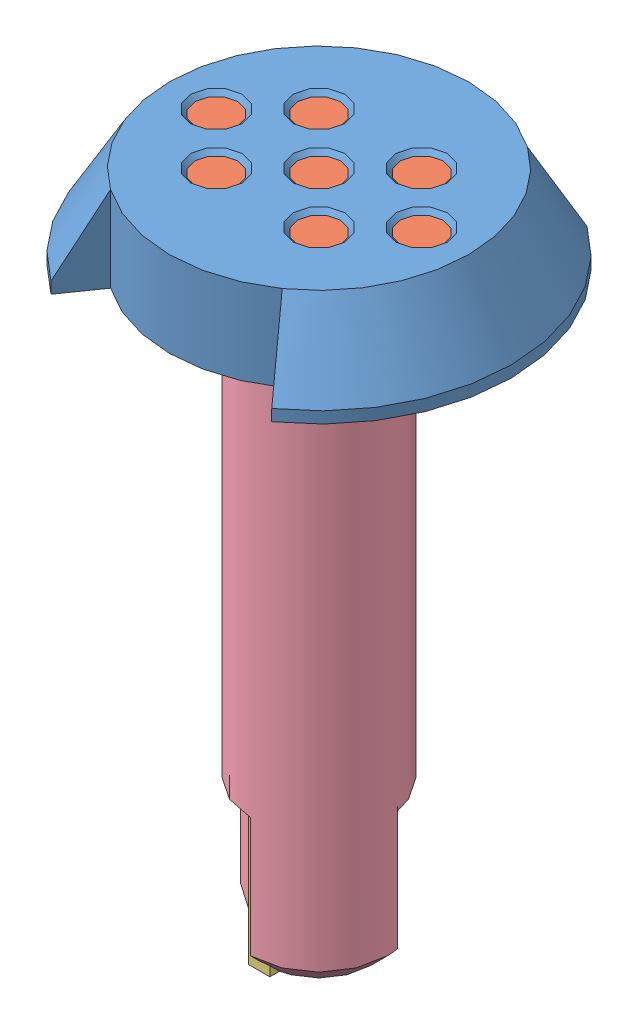
SolidWorks assembly inlet_axis, configuration Default. Lengths in mm.
Overall size (45 77.75 36.86).
4 component instances, 4 part files, 9 mates.
Components (placement in the parent):
- inlet_holder-1: inlet_holder [Default] at origin size (45 10 36.86)
- inlet_plate-1: inlet_plate [Default] at (0 9 0) x (-1 0 0) z (0 0 1) size (34 13 34)
- long_plate_d-1: long_plate_d [Default] at (0 -11.5 0) x (0 0 -1) z (0 1 0) size (14 8 68.25)
- long_plate_case_d-1: long_plate_case_d [Default] at (0 -67.75 0) x (0 0 -1) z (0 1 0) size (33 33 74.25)
Mates (geometry in assembly coordinates):
- Совпадение1: coincident anti-aligned: plane of inlet_holder-1 through (0 9 0) normal (0 -1 0); plane of inlet_plate-1 through (0 9 0) normal (0 1 0)
- Концентричный1: concentric anti-aligned: cylinder of inlet_holder-1 through (-12 0 0) axis (0 1 0) radius 2.5; cylinder of inlet_plate-1 through (-12 9.5 0) axis (0 -1 0) radius 2.5
- Концентричный2: concentric anti-aligned: cylinder of inlet_holder-1 through (12 0 0) axis (0 1 0) radius 2.5; cylinder of inlet_plate-1 through (12 9.5 0) axis (0 -1 0) radius 2.5
- Совпадение2: coincident anti-aligned: plane of inlet_plate-1 through (0 -3.5 0) normal (0 -1 0); plane of long_plate_d-1 through (0 -3.5 0) normal (0 1 0)
- Совпадение3: coincident aligned: plane of inlet_plate-1 through (-4 -3.5 4) normal (0 0 1); plane of long_plate_d-1 through (4 -13.5 4) normal (0 0 1)
- Совпадение4: coincident aligned: plane of inlet_plate-1 through (4 -3.5 4) normal (1 0 0); plane of long_plate_d-1 through (4 -13.5 -4) normal (1 0 0)
- Совпадение5: coincident anti-aligned: plane of long_plate_d-1 through (-1.25 -67.75 -7) normal (-1 0 0); plane of long_plate_case_d-1 through (-1.25 2.5 0) normal (1 0 0)
- Концентричный3: concentric anti-aligned: cylinder of inlet_holder-1 through (0 9 0) axis (0 -1 0) radius 17; cylinder of long_plate_case_d-1 through (0 11.7188 0) axis (0 1 0) radius 16.5
- Совпадение6: coincident aligned: plane of long_plate_d-1 through (0 -67.75 0) normal (0 -1 0); plane of long_plate_case_d-1 through (0 -67.75 0) normal (0 -1 0)
